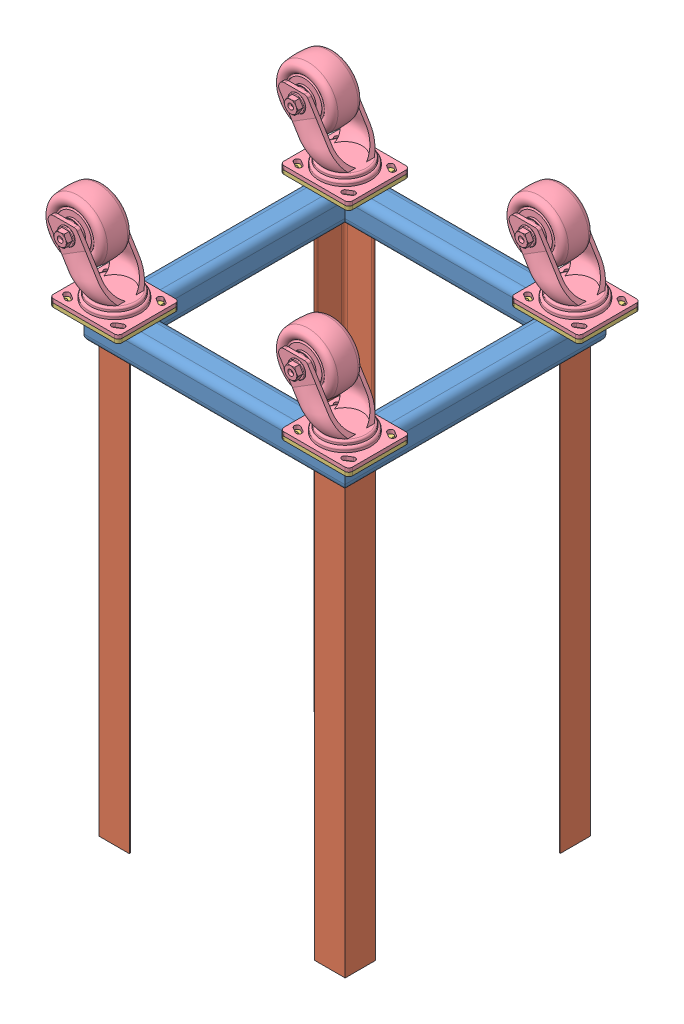
SolidWorks assembly Frame Assembly, configuration Default. Lengths in mm.
Overall size (805.82 911.23 805.82).
10 component instances, 4 part files, 27 mates.
Components (placement in the parent):
- Copy of Base Support^Frame Assembly-1: Copy of Base Support^Frame Assembly [Default<As Machined>] at origin size (434.34 50.8 434.34) (virtual)
- Copy of Legs^Frame Assembly-1: Copy of Legs^Frame Assembly [Default<As Machined>] at (3.4616 1288.0635 -34.29) x (-0.788011 0 0.615661) z (0.615661 0 0.788011) size (574.08 711.2 574.08) (virtual)
- Caster Plate-1: Caster Plate [Default] at (191.77 57.15 191.77) x (-1 0 0) z (0 0 1) size (114.3 6.35 101.6)
- Caster Plate-2: Caster Plate [Default] at (191.77 57.15 -191.77) x (-1 0 0) z (0 0 1) size (114.3 6.35 101.6)
- Caster Plate-3: Caster Plate [Default] at (-191.77 57.15 191.77) x (-1 0 0) z (0 0 1) size (114.3 6.35 101.6)
- Caster Plate-4: Caster Plate [Default] at (-191.77 57.15 -191.77) x (-1 0 0) z (0 0 1) size (114.3 6.35 101.6)
- Caster Wheels-2: Caster Wheels [2531T25] at (-236.22 149.225 191.77) x (1 0 0) z (0 0 -1) size (152.4 142.88 101.6)
- Caster Wheels-3: Caster Wheels [2531T25] at (147.32 149.225 191.77) x (1 0 0) z (0 0 -1) size (152.4 142.88 101.6)
- Caster Wheels-4: Caster Wheels [2531T25] at (-236.22 149.225 -191.77) x (1 0 0) z (0 0 -1) size (152.4 142.88 101.6)
- Caster Wheels-5: Caster Wheels [2531T25] at (147.32 149.225 -191.77) x (1 0 0) z (0 0 -1) size (152.4 142.88 101.6)
Mates (geometry in assembly coordinates):
- Coincident1: coincident anti-aligned: plane of Copy of Base Support^Frame Assembly-1 through (-204.47 0 179.07) normal (0 -1 0); plane of Copy of Legs^Frame Assembly-1 through (-204.5159 0 156.8909) normal (0 1 0)
- Width1: width aligned: plane of Copy of Legs^Frame Assembly-1; plane of Copy of Legs^Frame Assembly-1; plane of Copy of Base Support^Frame Assembly-1 through (166.37 12.7 204.47) normal (-1 0 0); plane of Copy of Base Support^Frame Assembly-1 through (-166.37 12.7 -204.47) normal (1 0 0)
- Width2: width aligned: plane of Copy of Legs^Frame Assembly-1 through (-153.721 0 204.521) normal (0 0 1); plane of Copy of Legs^Frame Assembly-1 through (-204.9901 0 -204.521) normal (0 0 -1); plane of Copy of Base Support^Frame Assembly-1 through (-204.47 12.7 166.37) normal (0 0 -1); plane of Copy of Base Support^Frame Assembly-1 through (204.47 12.7 -166.37) normal (0 0 1)
- Width3: width anti-aligned: plane of Caster Plate-1 through (134.62 50.8 140.97) normal (0 0 -1); plane of Caster Plate-1 through (134.62 50.8 242.57) normal (0 0 1); plane of Copy of Base Support^Frame Assembly-1 through (-204.47 12.7 166.37) normal (0 0 -1); plane of Copy of Base Support^Frame Assembly-1 through (-204.47 38.1 217.17) normal (0 0 1)
- Coincident2: coincident anti-aligned: plane of Copy of Base Support^Frame Assembly-1 through (204.47 50.8 204.47) normal (0 1 0); plane of Caster Plate-1 through (191.77 50.8 191.77) normal (0 -1 0)
- Width4: width anti-aligned: plane of Caster Plate-1 through (248.92 50.8 140.97) normal (1 0 0); plane of Caster Plate-1 through (134.62 50.8 140.97) normal (-1 0 0); plane of Copy of Base Support^Frame Assembly-1 through (166.37 12.7 204.47) normal (-1 0 0); plane of Copy of Base Support^Frame Assembly-1 through (217.17 38.1 204.47) normal (1 0 0)
- Coincident5: coincident anti-aligned: plane of Copy of Base Support^Frame Assembly-1 through (204.47 50.8 204.47) normal (0 1 0); plane of Caster Plate-2 through (191.77 50.8 -191.77) normal (0 -1 0)
- Width5: width anti-aligned: plane of Caster Plate-2 through (134.62 50.8 -242.57) normal (-1 0 0); plane of Caster Plate-2 through (248.92 50.8 -242.57) normal (1 0 0); plane of Copy of Base Support^Frame Assembly-1 through (217.17 38.1 204.47) normal (1 0 0); plane of Copy of Base Support^Frame Assembly-1 through (166.37 12.7 204.47) normal (-1 0 0)
- Width6: width aligned: plane of Caster Plate-2 through (134.62 50.8 -242.57) normal (0 0 -1); plane of Caster Plate-2 through (134.62 50.8 -140.97) normal (0 0 1); plane of Copy of Base Support^Frame Assembly-1 through (204.47 12.7 -166.37) normal (0 0 1); plane of Copy of Base Support^Frame Assembly-1 through (204.47 38.1 -217.17) normal (0 0 -1)
- Coincident8: coincident anti-aligned: plane of Copy of Base Support^Frame Assembly-1 through (-204.47 50.8 -204.47) normal (0 1 0); plane of Caster Plate-4 through (-191.77 50.8 -191.77) normal (0 -1 0)
- Width7: width anti-aligned: plane of Caster Plate-4 through (-248.92 50.8 -242.57) normal (0 0 -1); plane of Caster Plate-4 through (-248.92 50.8 -140.97) normal (0 0 1); plane of Copy of Base Support^Frame Assembly-1 through (204.47 38.1 -217.17) normal (0 0 -1); plane of Copy of Base Support^Frame Assembly-1 through (204.47 12.7 -166.37) normal (0 0 1)
- Width8: width aligned: plane of Caster Plate-4 through (-134.62 50.8 -242.57) normal (1 0 0); plane of Caster Plate-4 through (-248.92 50.8 -242.57) normal (-1 0 0); plane of Copy of Base Support^Frame Assembly-1 through (-166.37 12.7 -204.47) normal (1 0 0); plane of Copy of Base Support^Frame Assembly-1 through (-217.17 38.1 -204.47) normal (-1 0 0)
- Coincident9: coincident anti-aligned: plane of Copy of Base Support^Frame Assembly-1 through (-204.47 50.8 204.47) normal (0 1 0); plane of Caster Plate-3 through (-191.77 50.8 191.77) normal (0 -1 0)
- Width9: width aligned: plane of Caster Plate-3 through (-248.92 50.8 242.57) normal (0 0 1); plane of Caster Plate-3 through (-248.92 50.8 140.97) normal (0 0 -1); plane of Copy of Base Support^Frame Assembly-1 through (-204.47 12.7 166.37) normal (0 0 -1); plane of Copy of Base Support^Frame Assembly-1 through (-204.47 38.1 217.17) normal (0 0 1)
- Width10: width anti-aligned: plane of Caster Plate-3 through (-134.62 50.8 140.97) normal (1 0 0); plane of Caster Plate-3 through (-248.92 50.8 140.97) normal (-1 0 0); plane of Copy of Base Support^Frame Assembly-1 through (-217.17 38.1 -204.47) normal (-1 0 0); plane of Copy of Base Support^Frame Assembly-1 through (-166.37 12.7 -204.47) normal (1 0 0)
- Coincident10: coincident anti-aligned: plane of Caster Plate-3 through (-191.77 57.15 191.77) normal (0 1 0); plane of Caster Wheels-2 through (-248.92 57.15 140.97) normal (0 -1 0)
- Coincident11: coincident anti-aligned: plane of Caster Plate-1 through (191.77 57.15 191.77) normal (0 1 0); plane of Caster Wheels-3 through (134.62 57.15 140.97) normal (0 -1 0)
- Width13: width anti-aligned: plane of Caster Wheels-3 through (134.62 63.5 140.97) normal (0 0 -1); plane of Caster Wheels-3 through (134.62 63.5 242.57) normal (0 0 1); plane of Copy of Base Support^Frame Assembly-1 through (-204.47 38.1 217.17) normal (0 0 1); plane of Copy of Base Support^Frame Assembly-1 through (-204.47 12.7 166.37) normal (0 0 -1)
- Width14: width aligned: plane of Caster Wheels-3 through (248.92 57.15 140.97) normal (1 0 0); plane of Caster Wheels-3 through (134.62 57.15 140.97) normal (-1 0 0); plane of Copy of Base Support^Frame Assembly-1 through (166.37 12.7 204.47) normal (-1 0 0); plane of Copy of Base Support^Frame Assembly-1 through (217.17 38.1 204.47) normal (1 0 0)
- Coincident12: coincident anti-aligned: plane of Caster Plate-4 through (-191.77 57.15 -191.77) normal (0 1 0); plane of Caster Wheels-4 through (-248.92 57.15 -242.57) normal (0 -1 0)
- Width15: width anti-aligned: plane of Caster Wheels-4 through (-248.92 57.15 -242.57) normal (-1 0 0); plane of Caster Wheels-4 through (-134.62 57.15 -242.57) normal (1 0 0); plane of Copy of Base Support^Frame Assembly-1 through (-217.17 38.1 -204.47) normal (-1 0 0); plane of Copy of Base Support^Frame Assembly-1 through (-166.37 12.7 -204.47) normal (1 0 0)
- Width16: width anti-aligned: plane of Caster Wheels-4 through (-248.92 63.5 -242.57) normal (0 0 -1); plane of Caster Wheels-4 through (-248.92 63.5 -140.97) normal (0 0 1); plane of Copy of Base Support^Frame Assembly-1 through (204.47 12.7 -166.37) normal (0 0 1); plane of Copy of Base Support^Frame Assembly-1 through (204.47 38.1 -217.17) normal (0 0 -1)
- Coincident13: coincident anti-aligned: plane of Caster Plate-2 through (191.77 57.15 -191.77) normal (0 1 0); plane of Caster Wheels-5 through (134.62 57.15 -242.57) normal (0 -1 0)
- Width19: width anti-aligned: plane of Caster Wheels-2 through (-134.62 57.15 140.97) normal (1 0 0); plane of Caster Wheels-2 through (-248.92 57.15 140.97) normal (-1 0 0); plane of Copy of Base Support^Frame Assembly-1 through (-217.17 38.1 -204.47) normal (-1 0 0); plane of Copy of Base Support^Frame Assembly-1 through (-166.37 12.7 -204.47) normal (1 0 0)
- Width20: width anti-aligned: plane of Caster Wheels-2 through (-248.92 63.5 242.57) normal (0 0 1); plane of Caster Wheels-2 through (-248.92 63.5 140.97) normal (0 0 -1); plane of Copy of Base Support^Frame Assembly-1 through (-204.47 12.7 166.37) normal (0 0 -1); plane of Copy of Base Support^Frame Assembly-1 through (-204.47 38.1 217.17) normal (0 0 1)
- Width21: width anti-aligned: plane of Caster Wheels-5 through (134.62 63.5 -140.97) normal (0 0 1); plane of Caster Wheels-5 through (134.62 63.5 -242.57) normal (0 0 -1); plane of Copy of Base Support^Frame Assembly-1 through (204.47 38.1 -217.17) normal (0 0 -1); plane of Copy of Base Support^Frame Assembly-1 through (204.47 12.7 -166.37) normal (0 0 1)
- Width22: width aligned: plane of Caster Wheels-5 through (134.62 57.15 -242.57) normal (-1 0 0); plane of Caster Wheels-5 through (248.92 57.15 -242.57) normal (1 0 0); plane of Copy of Base Support^Frame Assembly-1 through (166.37 12.7 204.47) normal (-1 0 0); plane of Copy of Base Support^Frame Assembly-1 through (217.17 38.1 204.47) normal (1 0 0)
